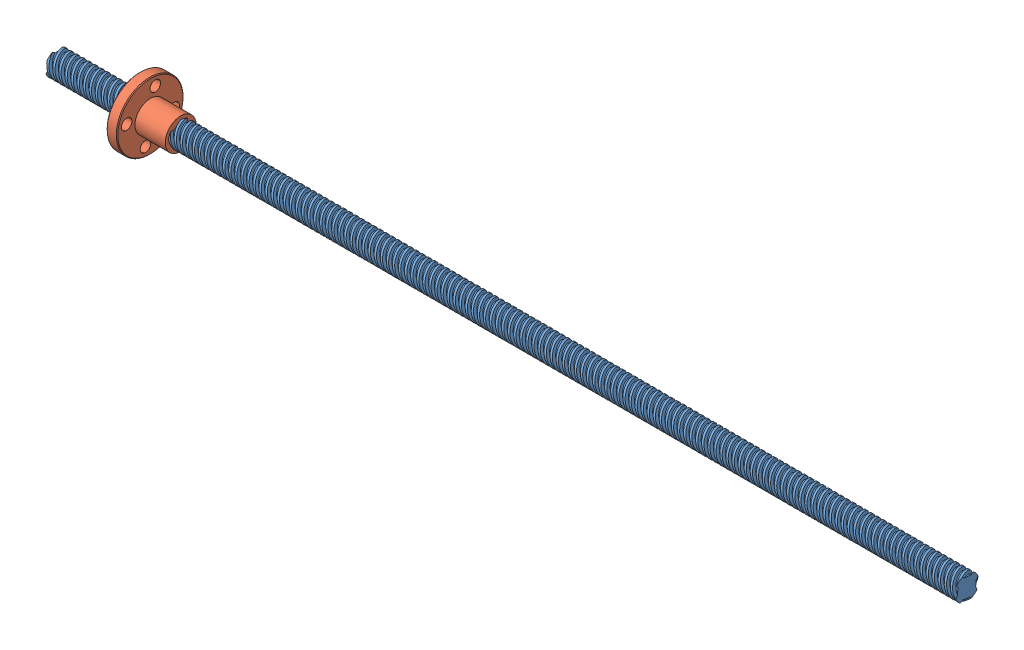
SolidWorks assembly TrapezoidalScrew&NutTHSL-300-8D, configuration Default. Lengths in mm.
Overall size (305.13 26 26).
2 component instances, 2 part files, 2 mates.
Components (placement in the parent):
- TrapezoidalScrewTHSL-300-8D-1: TrapezoidalScrewTHSL-300-8D [Default] at (-215.4207 11.88 23.3313) size (305.13 8.21 8.21)
- TrapezoidalNutTHSL-300-8D-1: TrapezoidalNutTHSL-300-8D [Default] at (-189.6802 11.88 23.3313) x (1 0 0) z (0 0.979312 -0.202355) size (16.71 22 22)
Mates (geometry in assembly coordinates):
- Concéntrica3: concentric aligned: cylinder of TrapezoidalScrewTHSL-300-8D-1 through (84.5793 11.88 23.3313) axis (-1 0 0) radius 4; cylinder of TrapezoidalNutTHSL-300-8D-1 through (110.3198 11.88 23.3313) axis (-1 0 0) radius 4
- Tornillo2: screw = 8 mm aligned: cylinder of TrapezoidalScrewTHSL-300-8D-1 through (84.5793 11.88 23.3313) axis (-1 0 0) radius 4; cylinder of TrapezoidalNutTHSL-300-8D-1 through (-174.6802 11.88 23.3313) axis (-1 0 0) radius 5.1
